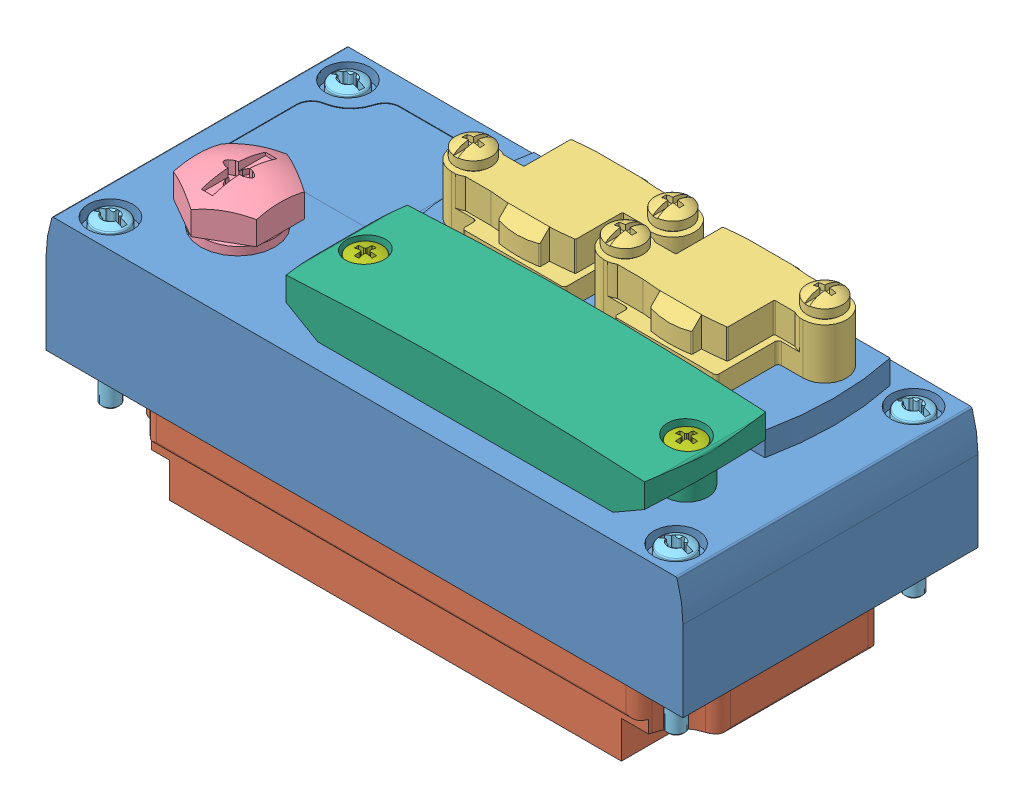
SolidWorks assembly 3473128 CPX-CEC-C1-V3, configuration Default. Lengths in mm.
Overall size (107.3 52.91 49.7).
12 component instances, 7 part files, 0 mates.
Components (placement in the parent):
- 3473128 CPX-CEC-C1-V3---(DE_1_0)-1: 3473128 CPX-CEC-C1-V3---(DE_1_0) [Default] at origin size (107.3 24 49.7)
- 694472 Elektromodul---(DE_0_0)-1: 694472 Elektromodul---(DE_0_0) [Default] at (0 -17.35 0) size (96.8 21.85 41)
- 534496 AK-RJ45-1: 534496 AK-RJ45 [Default] at (25.4 24 -10.5) size (32.9 16.66 20.2)
- 165592 ISK-M12-1: 165592 ISK-M12 [Default] at (-35.5 22.5 10.5) x (0 -1 0) z (-1 0 0) size (14.95 16.17 14)
- 534496 AK-RJ45-2: 534496 AK-RJ45 [Default] at (-0.2 24 -10.5) size (32.9 16.66 20.2)
- 550219 CPX-M-M3X22-4X-1: 550219 CPX-M-M3X22-4X [Default] at (47.65 17.9 20) x (0 -1 0) z (-1 0 0) size (27.4 5.6 5.6)
- 550219 CPX-M-M3X22-4X-2: 550219 CPX-M-M3X22-4X [Default] at (-47.65 17.9 20) x (0 -1 0) z (-1 0 0) size (27.4 5.6 5.6)
- 550219 CPX-M-M3X22-4X-3: 550219 CPX-M-M3X22-4X [Default] at (47.65 17.9 -20) x (0 -1 0) z (-1 0 0) size (27.4 5.6 5.6)
- 550219 CPX-M-M3X22-4X-4: 550219 CPX-M-M3X22-4X [Default] at (-47.65 17.9 -20) x (0 -1 0) z (-1 0 0) size (27.4 5.6 5.6)
- 533334 AK-SUB-9_15-B-1: 533334 AK-SUB-9_15-B [Default] at (-14.15 20 10.55) x (0 0 -1) z (1 0 0) size (20.4 8 61.86)
- DIN-7500 CEM3x10-H-1: DIN-7500 CEM3x10-H [Default] at (-14.15 24.7 10.55) x (0 -1 0) z (-1 0 0) size (12.38 5.6 5.6)
- DIN-7500 CEM3x10-H-2: DIN-7500 CEM3x10-H [Default] at (39.95 24.7 10.55) x (0 -1 0) z (-1 0 0) size (12.38 5.6 5.6)
